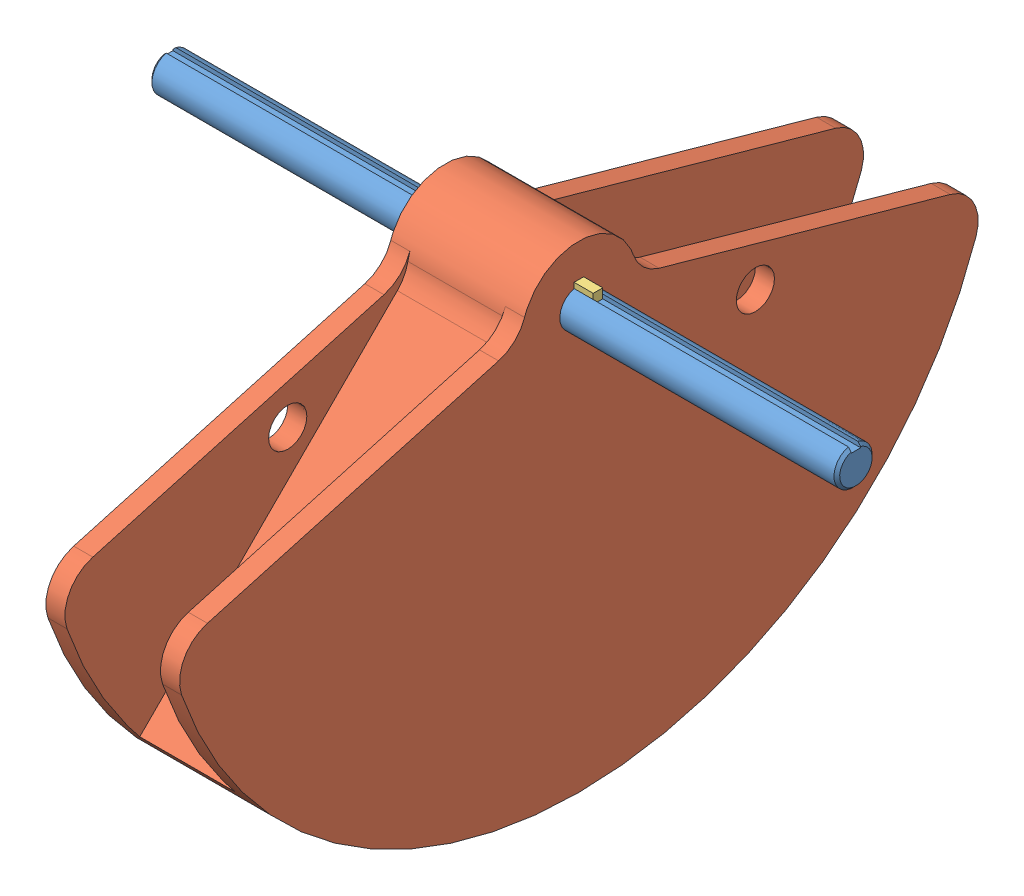
SolidWorks assembly SubAssembly_Pendulum, configuration Default. Lengths in mm.
Overall size (457.2 317.5 530.9).
3 component instances, 3 part files, 8 mates.
Components (placement in the parent):
- 1497K281_FULLY KEYED 1045 STEEL DRIVE SHAFT-2: 1497K281_FULLY KEYED 1045 STEEL DRIVE SHAFT [1497K281] at origin size (457.2 25.4 25.4)
- Pendulum_SemiCirc-1: Pendulum_SemiCirc [Default] x (0 0 1) z (-1 0 0) size (530.9 317.5 88.9)
- Keystock-1: Keystock [Default] at (6.35 12.7 0) size (101.6 6.35 6.35)
Mates (geometry in assembly coordinates):
- Concentric1: concentric anti-aligned: cylinder of 1497K281_FULLY KEYED 1045 STEEL DRIVE SHAFT-2 through (228.6 0 0) axis (-1 0 0) radius 12.7; cylinder of Pendulum_SemiCirc-1 through (-31.75 0 0) axis (1 0 0) radius 12.7
- Width1: width anti-aligned: plane of 1497K281_FULLY KEYED 1045 STEEL DRIVE SHAFT-2 through (228.6 0 0) normal (1 0 0); plane of 1497K281_FULLY KEYED 1045 STEEL DRIVE SHAFT-2 through (-228.6 0 0) normal (-1 0 0); plane of Pendulum_SemiCirc-1 through (-44.45 20.1797 60.2082) normal (-1 0 0); plane of Pendulum_SemiCirc-1 through (44.45 20.1797 -60.2082) normal (1 0 0)
- Coincident3: coincident aligned: plane of 1497K281_FULLY KEYED 1045 STEEL DRIVE SHAFT-2 through (-228.6 12.7 -3.175) normal (0 0 1); plane of Pendulum_SemiCirc-1 through (44.45 9.525 -3.175) normal (0 0 1)
- Coincident4: coincident anti-aligned: plane of 1497K281_FULLY KEYED 1045 STEEL DRIVE SHAFT-2 through (-228.6 12.7 -3.175) normal (0 0 1); plane of Keystock-1 through (57.15 9.525 -3.175) normal (0 0 -1)
- Coincident5: coincident anti-aligned: plane of 1497K281_FULLY KEYED 1045 STEEL DRIVE SHAFT-2 through (-228.6 9.525 3.175) normal (0 1 0); plane of Keystock-1 through (57.15 9.525 -3.175) normal (0 -1 0)
- Coincident6: coincident aligned: plane of Pendulum_SemiCirc-1 through (-44.45 20.1797 60.2082) normal (-1 0 0); plane of Keystock-1 through (-44.45 12.7 0) normal (-1 0 0)
- Coincident20: coincident: point of 1497K281_FULLY KEYED 1045 STEEL DRIVE SHAFT-2; plane of assembly
- Coincident21: coordinate: point of 1497K281_FULLY KEYED 1045 STEEL DRIVE SHAFT-2; point of assembly
